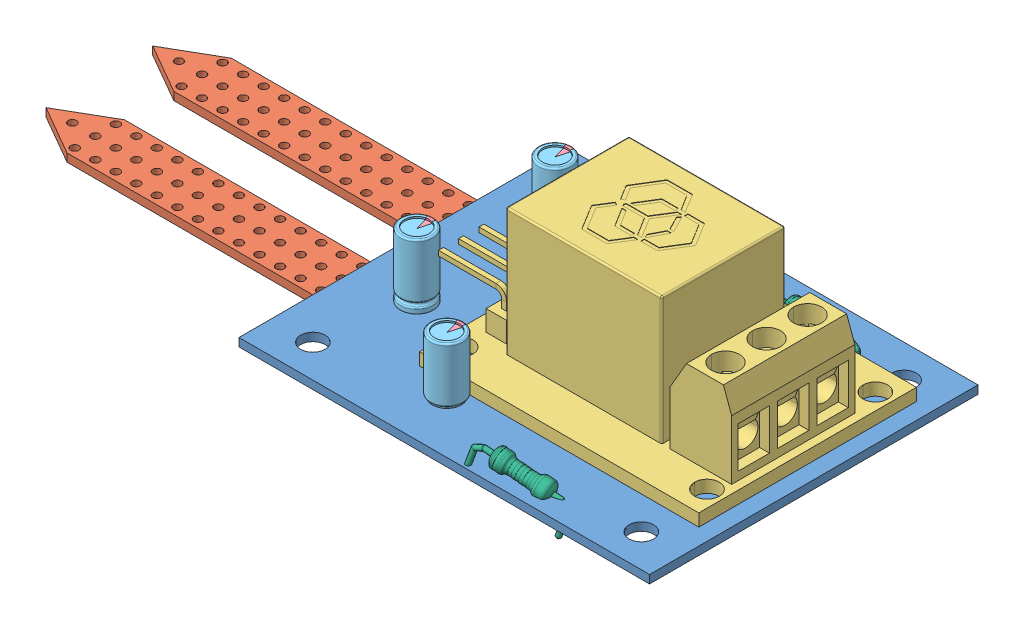
SolidWorks assembly Assem1, configuration Default. Lengths in mm.
Overall size (87 22.83 40.8).
18 component instances, 6 part files, 10 mates.
Components (placement in the parent):
- pcb_extension-1: pcb_extension [Default] at (18.6557 16.2827 31.8573) size (50 1 40)
- Soil Humidty sensor-1: Soil Humidty sensor [Default] at (13.6557 15.7827 31.8573) x (0 0 -1) z (-1 0 0) size (20 3.75 60.7)
- Relay.step-1: Relay.step [Default] at (24.6557 17.2827 30.6073) x (0 0 1) z (-1 0 0) size (26.5 20 38.75)
- 4x8x2mm.stp-1: 4x8x2mm.stp [Default] at (7.5312 13.6349 18.6867) size (4 12.8 4)
  - Part1.stp-1: Part1.stp [Default] at (-5.6305 3.8852 2.9319) size (1.04 12.8 2)
  - 4x11x2.54-2.stp-1: 4x11x2.54-2.stp [Default] at (-5.6305 3.8852 2.9319) size (4 12.8 3.93)
- Widerstand_100k.step-1: Widerstand_100k.step [Default] at (16.5962 18.7078 15.9948) size (11.38 4.9 2.3)
- 4x8x2mm.stp-2: 4x8x2mm.stp [Default] at (6.2432 13.2254 34.2164) size (4 12.8 4)
  - Part1.stp-1: Part1.stp [Default] at (-5.6305 3.8852 2.9319) size (1.04 12.8 2)
  - 4x11x2.54-2.stp-1: 4x11x2.54-2.stp [Default] at (-5.6305 3.8852 2.9319) size (4 12.8 3.93)
- 4x8x2mm.stp-3: 4x8x2mm.stp [Default] at (18.1873 12.3625 42.5138) size (4 12.8 4)
  - Part1.stp-1: Part1.stp [Default] at (-5.6305 3.8852 2.9319) size (1.04 12.8 2)
  - 4x11x2.54-2.stp-1: 4x11x2.54-2.stp [Default] at (-5.6305 3.8852 2.9319) size (4 12.8 3.93)
- Widerstand_100k.step-2: Widerstand_100k.step [Default] at (22.5048 15.1327 19.0755) x (0.887856 0 0.460122) z (0.460122 0 -0.887856) size (11.38 4.9 2.3)
- Widerstand_100k.step-3: Widerstand_100k.step [Default] at (28.1877 18.5589 16.2362) size (11.38 4.9 2.3)
- Widerstand_100k.step-4: Widerstand_100k.step [Default] at (24.6794 15.1327 35.9018) x (0.981215 0 0.192917) z (0.16467 -0.520959 -0.837547) size (11.38 4.9 2.3)
- Widerstand_100k.step-5: Widerstand_100k.step [Default] at (26.3473 18.2201 49.9184) x (0.943987 -0.276189 -0.180579) z (0.216205 0.104261 0.970765) size (11.38 4.9 2.3)
- Widerstand_100k.step-6: Widerstand_100k.step [Default] at (34.2035 15.1327 23.7122) x (0.974951 0 0.222421) z (0.222312 0.031322 -0.974472) size (11.38 4.9 2.3)
Mates (geometry in assembly coordinates):
- Coincident1: coincident: plane of pcb_extension-1 through (18.6557 16.2827 31.8573) normal (0 -1 0); plane of Soil Humidty sensor-1 through (4.8273 16.2827 40.8573) normal (0 1 0)
- Distance1: distance = 10 mm: line of Soil Humidty sensor-1 through (8.6557 16.2827 21.8573) axis (1 0 0); line of pcb_extension-1 through (43.6557 16.2827 11.8573) axis (-1 0 0)
- Coincident4: coincident: line of pcb_extension-1 through (-6.3443 16.2827 11.8573) axis (0 0 1); line of Soil Humidty sensor-1 through (-6.3443 16.2827 28.8573) axis (0 0 -1)
- Coincident5: coincident: plane of pcb_extension-1 through (18.6557 17.2827 31.8573) normal (0 1 0); plane of Relay.step-1 through (24.6557 17.2827 30.6073) normal (0 -1 0)
- Parallel3: parallel: line of pcb_extension-1 through (-6.3443 17.2827 51.8573) axis (1 0 0); line of Relay.step-1 through (7.6557 18.7827 43.8573) axis (1 0 0)
- Distance4: distance = 2 mm: line of Relay.step-1 through (41.6557 17.2827 43.8573) axis (0 0 -1); line of pcb_extension-1 through (43.6557 17.2827 51.8573) axis (0 0 -1)
- Distance5: distance = 8 mm: line of Relay.step-1 through (7.6557 17.2827 43.8573) axis (1 0 0); line of pcb_extension-1 through (-6.3443 17.2827 51.8573) axis (1 0 0)
- Tangent1: tangent: plane of pcb_extension-1 through (18.6557 16.2827 31.8573) normal (0 -1 0); cylinder of Widerstand_100k.step-4 through (27.3511 15.1327 36.427) axis (-0.981215 0 -0.192917) radius 1.15
- Tangent2: tangent: plane of pcb_extension-1 through (18.6557 16.2827 31.8573) normal (0 -1 0); cylinder of Widerstand_100k.step-2 through (24.9224 15.1327 20.3283) axis (-0.887856 0 -0.460122) radius 1.15
- Tangent3: tangent: plane of pcb_extension-1 through (18.6557 16.2827 31.8573) normal (0 -1 0); cylinder of Widerstand_100k.step-6 through (36.8582 15.1327 24.3178) axis (-0.974951 0 -0.222421) radius 1.15
